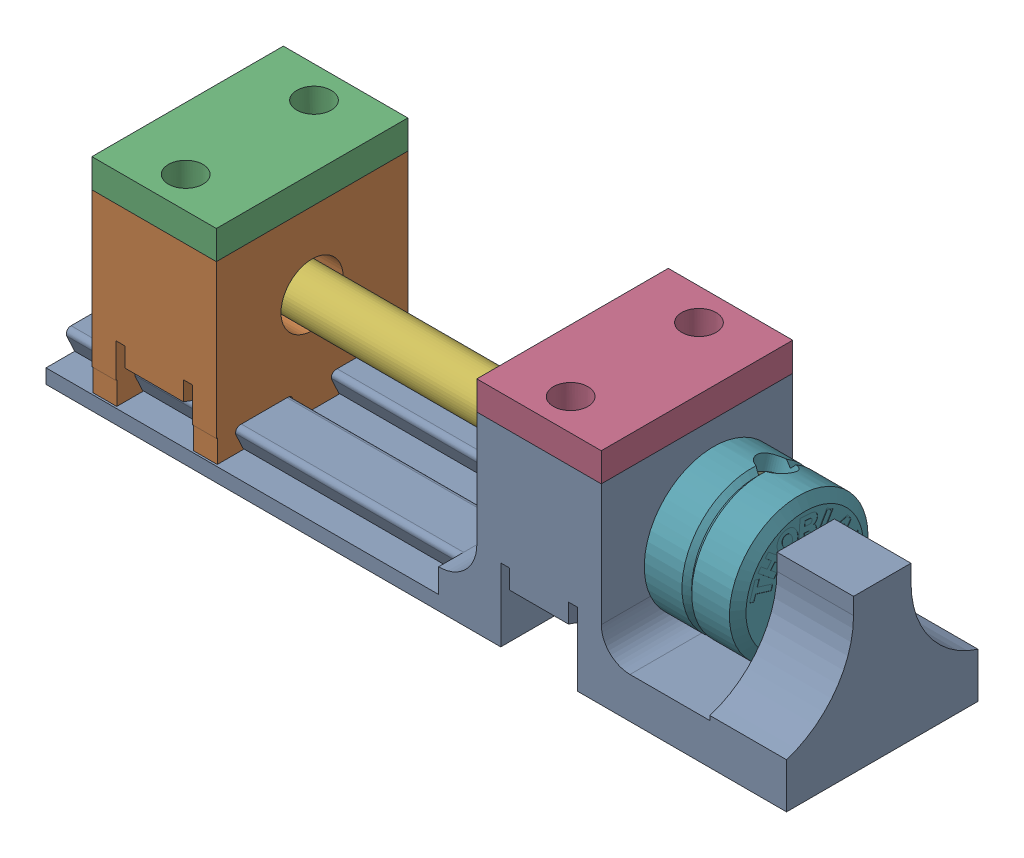
SolidWorks assembly thin_sliding_sample, configuration Default. Lengths in mm.
Overall size (77.35 23 20).
6 component instances, 5 part files, 13 mates.
Components (placement in the parent):
- sliding_sample_base-1: sliding_sample_base [Default] at (-36.1997 -3.8456 9.8155) size (77.35 20 20)
- sliding_rail_thin-1: sliding_rail_thin [Default] at (-47.4066 0.1544 -0.1845) x (0 0 1) z (-1 0 0) size (20 18.4 13)
- thin_top-1: thin_top [Default] at (-60.4066 16.1544 -0.1845) x (0 0 1) z (-1 0 0) size (20 3 13)
- thin_top-2: thin_top [Default] at (-20.1997 16.1544 -0.1845) x (0 0 1) z (-1 0 0) size (20 3 13)
- F19MS200-Solidworks-1: F19MS200-Solidworks [Default] at (-15.1074 4.2054 57.7563) x (0 -0.878477 -0.477785) z (0 0.477785 -0.878477) size (4.76 50.91 4.76)
- HKTS-5_64-Solidworks-1: HKTS-5_64-Solidworks [Default] at (-1.1455 8.407 8.7484) x (0 0.29504 0.955485) z (-1 0 0) size (14.48 14.48 16.51)
Mates (geometry in assembly coordinates):
- Parallel1: parallel aligned: plane of sliding_sample_base-1 through (-20.1997 0.1544 -50.8) normal (-1 0 0); plane of sliding_rail_thin-1 through (-60.4066 0.1544 -0.1845) normal (-1 0 0)
- Width1: width aligned: plane of sliding_sample_base-1 through (-84.5497 -3.8456 19.8155) normal (0 0 1); plane of sliding_rail_thin-1 through (-84.5497 -3.8456 -0.1845) normal (0 0 -1); plane of sliding_sample_base-1 through (-60.4066 0.1544 19.8155) normal (0 0 1); plane of sliding_rail_thin-1 through (-60.4066 0.1544 -0.1845) normal (0 0 -1)
- Coincident2: coincident aligned: plane of sliding_sample_base-1 through (-7.1997 16.1544 -50.8) normal (0 1 0); plane of sliding_rail_thin-1 through (-60.4066 16.1544 -0.1845) normal (0 1 0)
- Width2: width aligned: plane of sliding_rail_thin-1 through (-60.4066 0.1544 19.8155) normal (0 0 1); plane of thin_top-1 through (-60.4066 0.1544 -0.1845) normal (0 0 -1); plane of sliding_rail_thin-1 through (-60.4066 19.1544 19.8155) normal (0 0 1); plane of thin_top-1 through (-60.4066 19.1544 -0.1845) normal (0 0 -1)
- Width3: width aligned: plane of thin_top-1 through (-60.4066 19.1544 -0.1845) normal (-1 0 0); plane of sliding_rail_thin-1 through (-47.4066 19.1544 -0.1845) normal (1 0 0); plane of thin_top-1 through (-60.4066 0.1544 -0.1845) normal (-1 0 0); plane of sliding_rail_thin-1 through (-47.4066 0.1544 -0.1845) normal (1 0 0)
- Coincident3: coincident anti-aligned: plane of sliding_rail_thin-1 through (-60.4066 16.1544 -0.1845) normal (0 1 0); plane of thin_top-1 through (-60.4066 16.1544 -0.1845) normal (0 -1 0)
- Width4: width aligned: plane of sliding_sample_base-1 through (-20.1997 0.1544 -50.8) normal (-1 0 0); plane of thin_top-2 through (-7.1997 0.1544 49.8155) normal (1 0 0); plane of sliding_sample_base-1 through (-20.1997 19.1544 -0.1845) normal (-1 0 0); plane of thin_top-2 through (-7.1997 19.1544 -0.1845) normal (1 0 0)
- Width5: width aligned: plane of sliding_sample_base-1 through (-84.5497 -3.8456 19.8155) normal (0 0 1); plane of thin_top-2 through (-84.5497 -3.8456 -0.1845) normal (0 0 -1); plane of sliding_sample_base-1 through (-20.1997 19.1544 19.8155) normal (0 0 1); plane of thin_top-2 through (-20.1997 19.1544 -0.1845) normal (0 0 -1)
- Coincident4: coincident anti-aligned: plane of sliding_sample_base-1 through (-7.1997 16.1544 -50.8) normal (0 1 0); plane of thin_top-2 through (-20.1997 16.1544 -0.1845) normal (0 -1 0)
- Concentric1: concentric anti-aligned: circle of sliding_sample_base-1; circle of HKTS-5_64-Solidworks-1
- Concentric2: concentric anti-aligned: circle of sliding_sample_base-1; circle of F19MS200-Solidworks-1
- Distance1: distance = 1 mm anti-aligned: plane of HKTS-5_64-Solidworks-1 through (-6.1047 14.0202 8.0042) normal (-1 0 0); plane of F19MS200-Solidworks-1 through (-7.1047 6.3135 8.8143) normal (1 0 0)
- Width6: width anti-aligned: plane of sliding_sample_base-1 through (-6.1997 8.1544 9.8155) normal (1 0 0); plane of HKTS-5_64-Solidworks-1 through (4.1503 -3.8456 9.8155) normal (-1 0 0); plane of sliding_sample_base-1 through (-6.1047 14.0202 8.0042) normal (-1 0 0); plane of HKTS-5_64-Solidworks-1 through (4.0553 14.0202 8.0042) normal (1 0 0)
